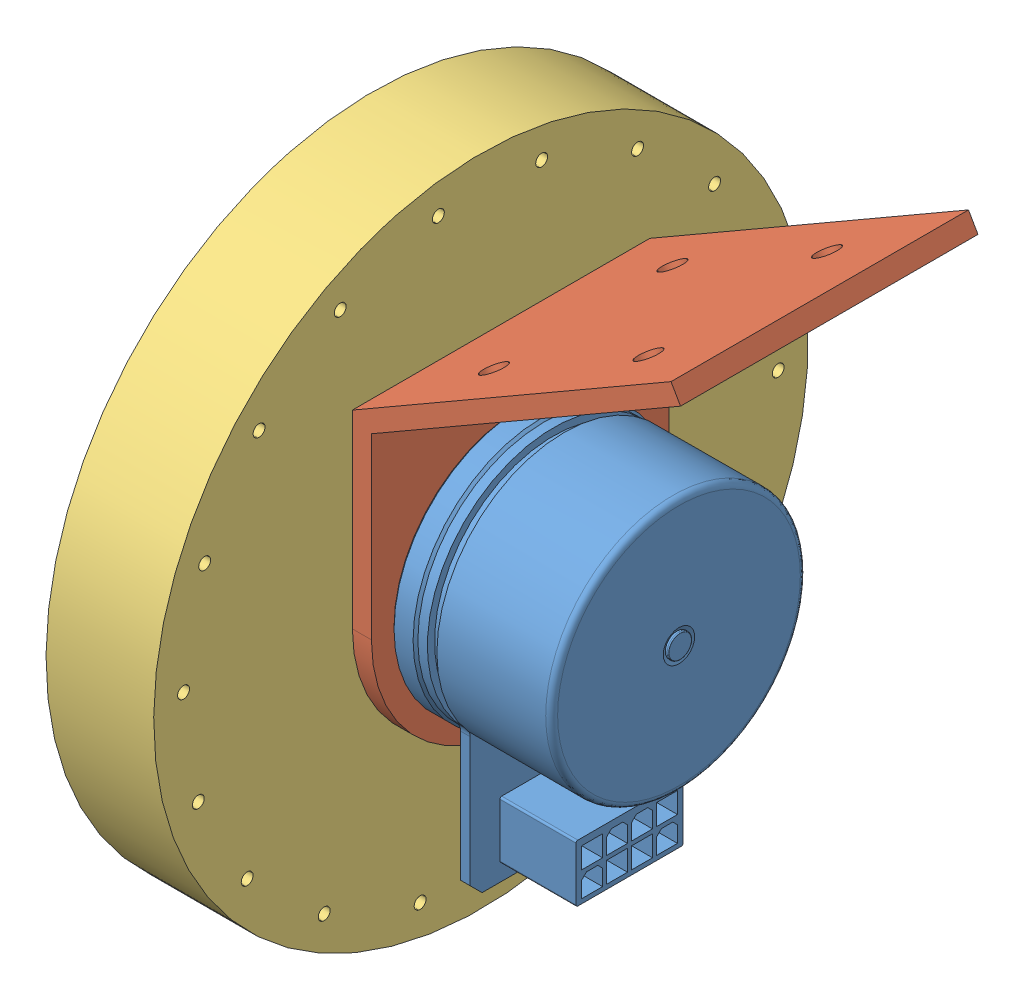
SolidWorks assembly SE_01_1_5000, configuration Default. Lengths in mm.
Overall size (91.64 138.87 138.87).
6 component instances, 4 part files, 11 mates.
Components (placement in the parent):
- SE_01_1_5001-1: SE_01_1_5001 [Default] at origin size (47.5 62.1 43.2)
- SE_01_1_5002-1: SE_01_1_5002 [Default] x (0 0 1) z (-1 0 0) size (50 87.77 55.16)
- SE_01_1_5003-1: SE_01_1_5003 [Default] at (-14.6 0 0) x (0 0.949894 0.312571) z (-1 0 0) size (110 110 53.58)
- pan head cross recess screw_iso-1: pan head cross recess screw_iso [ISO 7045 - M2.5 x 8 - Z - 8N] at (-5.3 -5.5 -9.5263) size (10.05 5 5)
- pan head cross recess screw_iso-2: pan head cross recess screw_iso [ISO 7045 - M2.5 x 8 - Z - 8N] at (-5.3 -5.5 9.5263) size (10.05 5 5)
- pan head cross recess screw_iso-3: pan head cross recess screw_iso [ISO 7045 - M2.5 x 8 - Z - 8N] at (-5.3 11 0) size (10.05 5 5)
Mates (geometry in assembly coordinates):
- Coincident1: coincident anti-aligned: plane of SE_01_1_5001-1 through (0 0 0) normal (-1 0 0); plane of SE_01_1_5002-1 through (0 0 0) normal (1 0 0)
- Concentric1: concentric aligned: cylinder of SE_01_1_5001-1 through (-3.2 0 0) axis (1 0 0) radius 6; cylinder of SE_01_1_5002-1 through (-77.5303 0 0) axis (1 0 0) radius 6.2732
- Concentric2: concentric anti-aligned: cylinder of SE_01_1_5001-1 through (0 11 0) axis (-1 0 0) radius 1.25; cylinder of SE_01_1_5002-1 through (-77.5303 11 0) axis (1 0 0) radius 1.25
- Concentric3: concentric anti-aligned: cylinder of SE_01_1_5002-1 through (-77.5303 11 0) axis (1 0 0) radius 1.25; cylinder of pan head cross recess screw_iso-3 through (-30.7 11 0) axis (-1 0 0) radius 1.25
- Concentric4: concentric anti-aligned: cylinder of SE_01_1_5002-1 through (-77.5303 -5.5 9.5263) axis (1 0 0) radius 1.25; cylinder of pan head cross recess screw_iso-2 through (-30.7 -5.5 9.5263) axis (-1 0 0) radius 1.25
- Concentric5: concentric anti-aligned: cylinder of SE_01_1_5002-1 through (-77.5303 -5.5 -9.5263) axis (1 0 0) radius 1.25; cylinder of pan head cross recess screw_iso-1 through (-30.7 -5.5 -9.5263) axis (-1 0 0) radius 1.25
- Coincident2: coincident anti-aligned: plane of SE_01_1_5002-1 through (-3.2 0 0) normal (-1 0 0); plane of pan head cross recess screw_iso-2 through (-3.2 -4.25 9.5263) normal (1 0 0)
- Coincident3: coincident anti-aligned: plane of SE_01_1_5002-1 through (-3.2 0 0) normal (-1 0 0); plane of pan head cross recess screw_iso-1 through (-3.2 -4.25 -9.5263) normal (1 0 0)
- Coincident4: coincident anti-aligned: plane of SE_01_1_5002-1 through (-3.2 0 0) normal (-1 0 0); plane of pan head cross recess screw_iso-3 through (-3.2 12.25 0) normal (1 0 0)
- Concentric6: concentric aligned: cylinder of SE_01_1_5001-1 through (-20.1 0 0) axis (1 0 0) radius 2; cylinder of SE_01_1_5003-1 through (-22.6 0 0) axis (1 0 0) radius 2
- Coincident5: coincident anti-aligned: plane of SE_01_1_5001-1 through (-20.6 0 0) normal (-1 0 0); plane of SE_01_1_5003-1 through (-20.6 0 0) normal (1 0 0)
